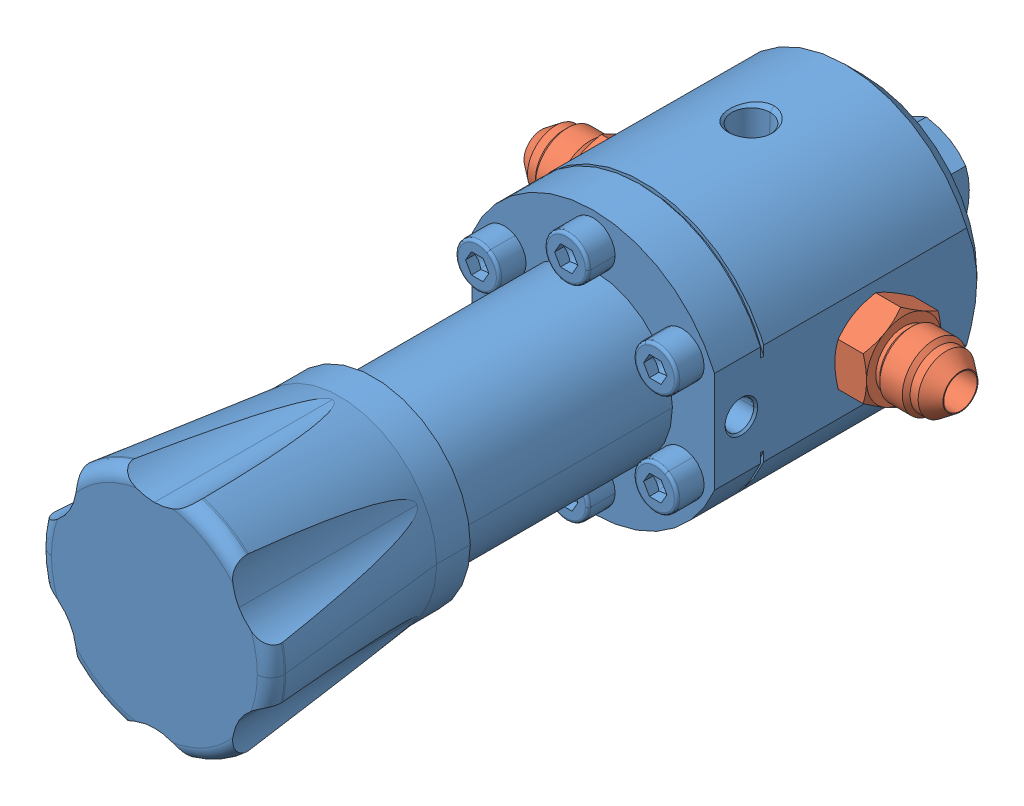
SolidWorks assembly PRV-1 & PRV-2 Assembly, configuration Default. Lengths in mm.
Overall size (144.32 78.02 230.14).
3 component instances, 2 part files, 2 mates.
Components (placement in the parent):
- PRV-1&2_RSHN4-02-6-VVK-Swagelok-1: PRV-1&2_RSHN4-02-6-VVK-Swagelok [Default] at origin size (72 78.02 230.14)
- 0500_OD_JIC_to_0500_NPT-1: 0500_OD_JIC_to_0500_NPT [50715K802] at (39.556 0 53.086) x (1 0 0) z (0 0.0006 1) size (55.21 25.66 22.23)
- 0500_OD_JIC_to_0500_NPT-2: 0500_OD_JIC_to_0500_NPT [50715K802] at (-39.556 0 53.086) x (-1 0 0) z (0 -0.0006 -1) size (55.21 25.66 22.23)
Mates (geometry in assembly coordinates):
- Concentric1: concentric aligned: cone of PRV-1&2_RSHN4-02-6-VVK-Swagelok-1 through (28.4887 0 53.086) axis (-1 0 0); cone of 0500_OD_JIC_to_0500_NPT-1 through (36 0 53.086) axis (-1 0 0)
- Coincident1: coincident anti-aligned: plane of PRV-1&2_RSHN4-02-6-VVK-Swagelok-1 through (36 0 125.212) normal (1 0 0); plane of 0500_OD_JIC_to_0500_NPT-1 through (36 19.2541 64.187) normal (-1 0 0)
